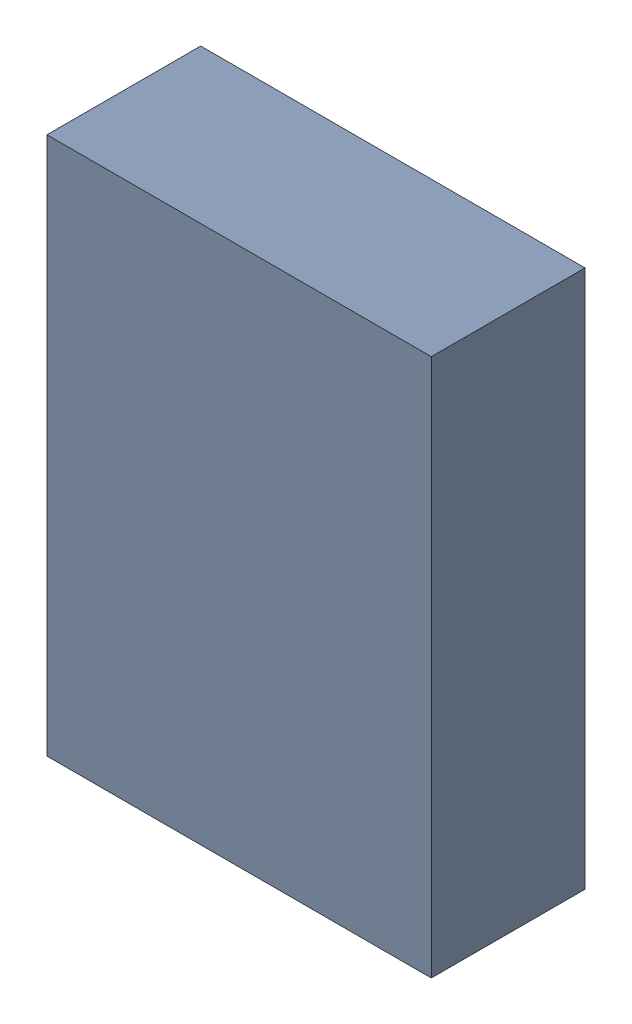
SolidWorks assembly Kanaloa_v2.0.0_Power_3, configuration Default. Lengths in mm.
Overall size (2.5 3.5 1).
2 component instances, 1 part files, 0 mates.
Components (placement in the parent):
- 378153280-1: 378153280 [Default] at (115.574 98.2218 0) size (2.5 3.5 1)
  - Extruded-1: Extruded [Default] at origin size (2.5 3.5 1)
